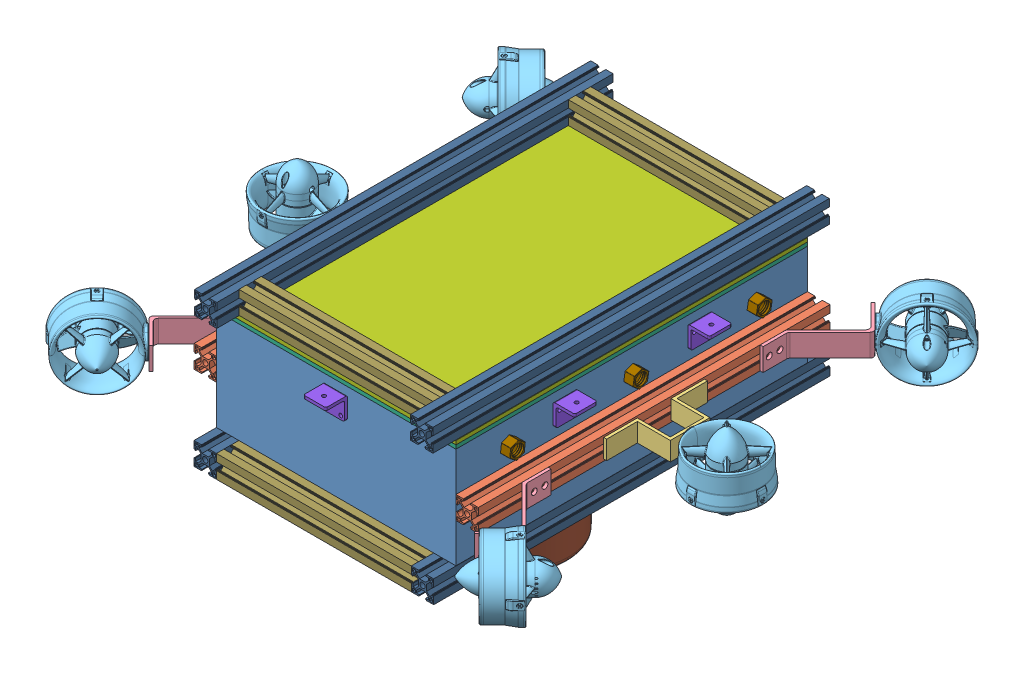
SolidWorks assembly model, configuration Default. Lengths in mm.
Overall size (689.81 332.5 699.39).
55 component instances, 29 part files, 15 mates.
Components (placement in the parent):
- assembly v17.step-1: assembly v17.step [Default] at origin size (689.81 332.5 699.39)
  - AUV hull.step-1: AUV hull.step [Default] at origin size (320 135 470)
  - side rail.step-1: side rail.step [Default] at (-0.2947 -450.131 -470) size (30.1 30.09 470)
  - side thruster mount.step-1: side thruster mount.step [Default] at (-190.1023 5 -167.5) x (0 0 -1) z (0 -1 0) size (135 48.07 25)
  - Thuruster mount.step-1: Thuruster mount.step [Default] at (190.1023 7.5 -93.2097) x (0 0 1) z (0 -1 0) size (126.22 60.15 30)
  - T100-ASM-CCW-THRUSTER-R1.step-1: T100-ASM-CCW-THRUSTER-R1.step [Default] at (-271.4208 -7.5 -518.4287) x (0 -1 0) z (-0.707107 0 0.707107) size (96.67 97.34 100.86)
  - Gasket.step-1: Gasket.step [Default] at (-160 60 -470) x (1 0 0) z (0 1 0) size (320 470 5)
  - lid.step-1: lid.step [Default] at (0 65 -235) x (1 0 0) z (0 1 0) size (320 470 5)
  - hull clamp.step-1: hull clamp.step [Default] at (-14.94 50 0) size (30 29 29)
  - penetrator_1-2_20.step-1: penetrator_1-2_20.step [Default] at (-172.7 30 -400) x (0 -0.795727 -0.605656) z (1 0 0) size (22.43 19.56 30.49)
  - down rail.step-1: down rail.step [Default] at (-320.5626 -532.5855 -500) size (30 30 530)
  - Weights.step-1: Weights.step [Default] at origin size (150 157.5 150)
  - side rail.step-2: side rail.step [Default] at (0.2947 435.131 -470) x (-1 0 0) z (0 0 1) size (30.1 30.09 470)
  - side thruster mount.step-2: side thruster mount.step [Default] at (190.1023 5 -302.5) x (0 0 1) z (0 -1 0) size (135 48.07 25)
  - Thuruster mount.step-2: Thuruster mount.step [Default] at (190.1023 -22.5 -376.6569) x (0 0 -1) z (0 1 0) size (126.22 60.15 30)
  - Thuruster mount.step-3: Thuruster mount.step [Default] at (-190.1023 7.5 -376.6569) x (0 0 -1) z (0 -1 0) size (126.22 60.15 30)
  - Thuruster mount.step-4: Thuruster mount.step [Default] at (-190.1023 -22.5 -93.3431) x (0 0 1) z (0 1 0) size (126.22 60.15 30)
  - T100-ASM-CCW-THRUSTER-R1.step-2: T100-ASM-CCW-THRUSTER-R1.step [Default] at (271.4208 -7.5 -518.4287) x (0 1 0) z (0.707107 0 0.707107) size (96.67 97.34 100.86)
  - T100-ASM-CCW-THRUSTER-R1.step-3: T100-ASM-CCW-THRUSTER-R1.step [Default] at (271.4208 -7.5 48.5622) x (0 -1 0) z (0.707107 0 -0.707107) size (96.67 97.34 100.86)
  - T100-ASM-CCW-THRUSTER-R1.step-4: T100-ASM-CCW-THRUSTER-R1.step [Default] at (-271.4208 -7.5 48.4287) x (0 1 0) z (-0.707107 0 -0.707107) size (96.67 97.34 100.86)
  - T100-ASM-CCW-THRUSTER-R1.step-5: T100-ASM-CCW-THRUSTER-R1.step [Default] at (-287.1745 -2.2482 -235) x (0 0 1) z (0 1 0) size (96.67 97.34 100.86)
  - T100-ASM-CCW-THRUSTER-R1.step-6: T100-ASM-CCW-THRUSTER-R1.step [Default] at (287.1745 -12.7518 -235) x (0 0 1) z (0 -1 0) size (96.67 97.34 100.86)
  - hull clamp.step-2: hull clamp.step [Default] at (14.94 50 -470) x (-1 0 0) z (0 0 -1) size (30 29 29)
  - hull clamp.step-3: hull clamp.step [Default] at (160 50 -129.94) x (0 0 -1) z (1 0 0) size (30 29 29)
  - hull clamp.step-4: hull clamp.step [Default] at (160 50 -310.06) x (0 0 -1) z (1 0 0) size (30 29 29)
  - hull clamp.step-5: hull clamp.step [Default] at (-160 50 -159.94) x (0 0 1) z (-1 0 0) size (30 29 29)
  - hull clamp.step-6: hull clamp.step [Default] at (-160 50 -340.06) x (0 0 1) z (-1 0 0) size (30 29 29)
  - penetrator_1-2_20.step-2: penetrator_1-2_20.step [Default] at (-172.7 30 -235) x (0 -0.689633 -0.724159) z (1 0 0) size (22.43 19.56 30.49)
  - penetrator_1-2_20.step-3: penetrator_1-2_20.step [Default] at (-172.7 30 -70) x (0 -0.591811 -0.806077) z (1 0 0) size (22.43 19.56 30.49)
  - penetrator_1-2_20.step-4: penetrator_1-2_20.step [Default] at (172.7 30 -70) x (0 0.596429 0.802666) z (-1 0 0) size (22.43 19.56 30.49)
  - penetrator_1-2_20.step-5: penetrator_1-2_20.step [Default] at (172.7 30 -235) x (0 0.63924 0.769007) z (-1 0 0) size (22.43 19.56 30.49)
  - penetrator_1-2_20.step-6: penetrator_1-2_20.step [Default] at (172.7 30 -400) x (0 0.646691 0.762752) z (-1 0 0) size (22.43 19.56 30.49)
  - down rail.step-2: down rail.step [Default] at (-30.0269 -532.5855 -500) size (30 30 530)
  - bottom rail.step-1: bottom rail.step [Default] at (130.2721 -265.2947 457.5855) x (0 1 0) z (-1 0 0) size (30 30 260.54)
  - down rail.step-3: down rail.step [Default] at (-31.0269 -357.5855 -500) size (30 30 530)
  - down rail.step-4: down rail.step [Default] at (-320.0626 -357.5855 -500) size (30 30 530)
  - bottom rail.step-2: bottom rail.step [Default] at (130.2679 -90.2947 -12.4145) x (0 1 0) z (-1 0 0) size (30 30 260.54)
  - bottom rail.step-3: bottom rail.step [Default] at (130.2679 -90.2947 427.5855) x (0 1 0) z (-1 0 0) size (30 30 260.54)
  - bottom rail(Mirror).step-1: bottom rail(Mirror).step [Default] at (130.2721 -265.2947 -927.5855) x (0 1 0) z (1 0 0) size (30 30 260.54)
- hull_collision-1: hull_collision [Default] at origin size (320.54 205.01 530) (hidden)
- port_rail-1: port_rail [Default] at (323.8753 3.3462 -173.0366) size (30.1 30.05 470) (hidden)
- star_rail-1: star_rail [Default] at (-15.202 -2.9527 -4.1456) size (30.1 30.09 470) (hidden)
- weight_collision-1: weight_collision [Default] at (0 7.5 0) size (150 150 150) (hidden)
- thruster_1_mount-1: thruster_1_mount [Default] at (0.2679 0 0) size (60.15 30 126.22) (hidden)
- thruster_1-1: thruster_1 [Default] at (0.1339 0 0.1339) size (140.71 98 140.71) (hidden)
- thruster_2_mount-1: thruster_2_mount [Default] at (0.2679 0 0) size (48.07 25 135) (hidden)
- thruster_2-1: thruster_2 [Default] at (0.2679 0 0) size (98 101 98) (hidden)
- thruster_3_mount-1: thruster_3_mount [Default] at (0.2679 0 0) size (60.15 30 126.22) (hidden)
- thruster_3-2: thruster_3 [Default] at (0.1339 0 -0.1339) size (140.71 98 140.71) (hidden)
- thruster_4_mount-1: thruster_4_mount [Default] at (-0.2679 0 0) size (60.15 30 126.22) (hidden)
- thruster_4-1: thruster_4 [Default] at (-0.1339 0 -0.1339) size (140.71 98 140.71) (hidden)
- thruster_5_mount-1: thruster_5_mount [Default] at (-0.2679 0 0) size (48.07 25 135) (hidden)
- thruster_5-1: thruster_5 [Default] at (-0.2679 0 0) size (98 101 98) (hidden)
- thruster_6_mount-1: thruster_6_mount [Default] at (-0.2679 0 0) size (60.15 30 126.22) (hidden)
- thruster_6-1: thruster_6 [Default] at (-0.1339 0 0.1339) size (140.71 98 140.71) (hidden)
Mates (geometry in assembly coordinates):
- Lock8: lock: unknown of hull_collision-1; unknown of port_rail-1
- Lock9: lock: unknown of hull_collision-1; unknown of weight_collision-1
- Lock10: lock: unknown of port_rail-1; unknown of thruster_1_mount-1
- Lock11: lock: unknown of thruster_1_mount-1; unknown of thruster_1-1
- Lock12: lock: unknown of port_rail-1; unknown of thruster_2_mount-1
- Lock13: lock: unknown of thruster_2_mount-1; unknown of thruster_2-1
- Lock14: lock: unknown of port_rail-1; unknown of thruster_3_mount-1
- Lock15: lock: unknown of thruster_3_mount-1; unknown of thruster_3-2
- Lock16: lock: unknown of hull_collision-1; unknown of star_rail-1
- Lock17: lock: unknown of star_rail-1; unknown of thruster_6_mount-1
- Lock18: lock: unknown of thruster_6_mount-1; unknown of thruster_6-1
- Lock19: lock: unknown of star_rail-1; unknown of thruster_5_mount-1
- Lock20: lock: unknown of thruster_5_mount-1; unknown of thruster_5-1
- Lock21: lock: unknown of star_rail-1; unknown of thruster_4_mount-1
- Lock22: lock: unknown of thruster_4_mount-1; unknown of thruster_4-1
